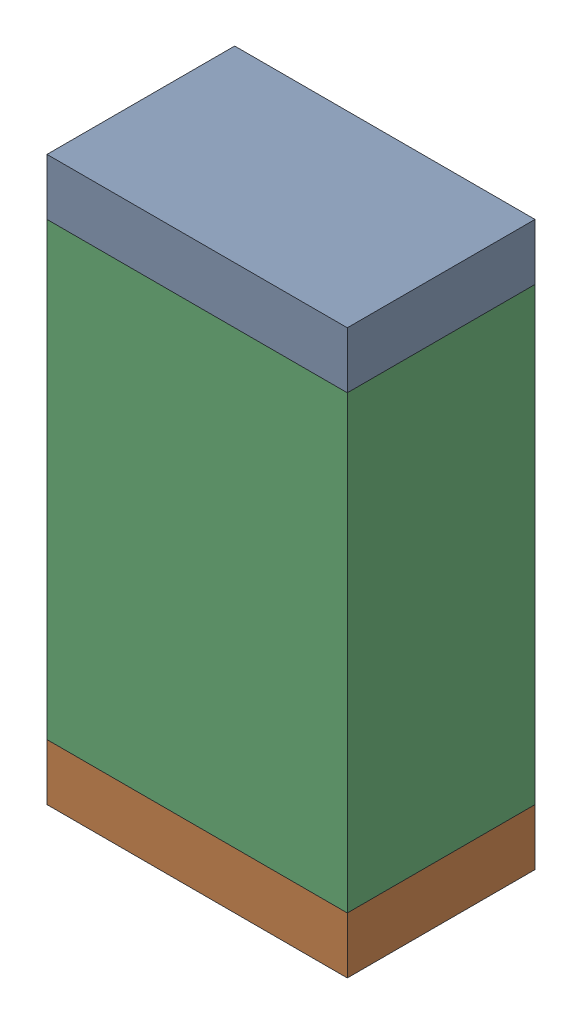
SolidWorks assembly R35, configuration Default. Lengths in mm.
Overall size (0.8 1.5 0.5).
6 component instances, 2 part files, 0 mates.
Components (placement in the parent):
- 810156592-1: 810156592 [Default] at (133 51.225 0) size (0.8 0.15 0.5)
  - Extruded_7-1: Extruded_7 [Default] at origin size (0.8 0.15 0.5)
- 810156592-2: 810156592 [Default] at (133 49.875 0) size (0.8 0.15 0.5)
  - Extruded_7-1: Extruded_7 [Default] at origin size (0.8 0.15 0.5)
- 810156976-1: 810156976 [Default] at (133 50.55 0) size (0.8 1.2 0.5)
  - Extruded_6-1: Extruded_6 [Default] at origin size (0.8 1.2 0.5)
